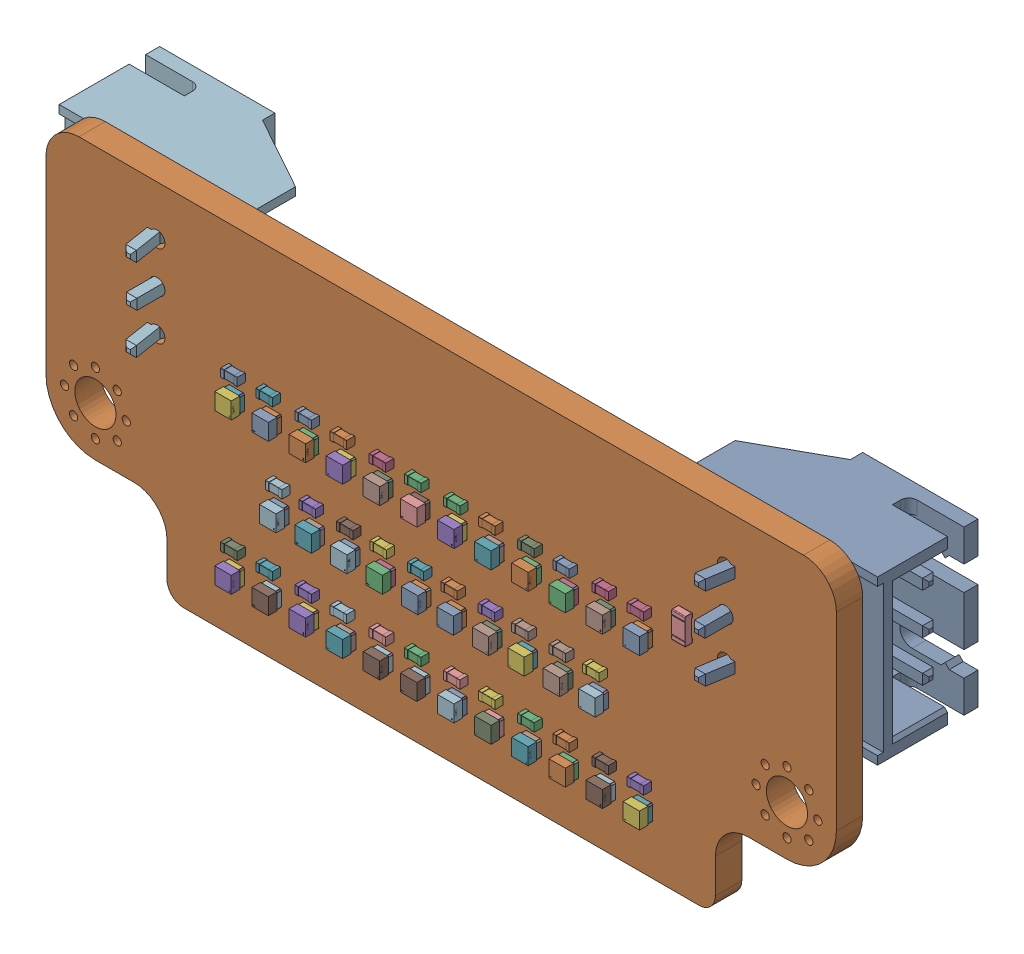
SolidWorks assembly head_logic_display(2), configuration Default. Lengths in mm.
Overall size (49.7 21.59 9.5).
143 component instances, 5 part files, 0 mates.
Components (placement in the parent):
- LED-SMD_4P-L1.0-W1.0-TL_XL-1010RGBC-WS2812B-1: LED-SMD_4P-L1.0-W1.0-TL_XL-1010RGBC-WS2812B [Default] at (-7.892 -7.295 1.65) x (0 1 0) z (0 0 1) size (1 1 0.81)
  - LED-SMD_4P-L1.0-W1.0-TL_XL-1010RGBC-WS2812B-0-1: LED-SMD_4P-L1.0-W1.0-TL_XL-1010RGBC-WS2812B-0 [Default] at origin size (1 1 0.81)
- C_0402_1005Metric-1: C_0402_1005Metric [Default] at (-10.206 3.245 1.65) x (-1 0 0) z (0 0 1) size (1 0.5 0.5)
  - C_0402_1005Metric-1-1: C_0402_1005Metric-1 [Default] at origin size (1 0.5 0.5)
- LED-SMD_4P-L1.0-W1.0-TL_XL-1010RGBC-WS2812B-2: LED-SMD_4P-L1.0-W1.0-TL_XL-1010RGBC-WS2812B [Default] at (9.7 -2.705 1.65) size (1 1 0.81)
  - LED-SMD_4P-L1.0-W1.0-TL_XL-1010RGBC-WS2812B-0-1: LED-SMD_4P-L1.0-W1.0-TL_XL-1010RGBC-WS2812B-0 [Default] at origin size (1 1 0.81)
- C_0402_1005Metric-2: C_0402_1005Metric [Default] at (7.826 -5.905 1.65) x (-1 0 0) z (0 0 1) size (1 0.5 0.5)
  - C_0402_1005Metric-1-1: C_0402_1005Metric-1 [Default] at origin size (1 0.5 0.5)
- LED-SMD_4P-L1.0-W1.0-TL_XL-1010RGBC-WS2812B-3: LED-SMD_4P-L1.0-W1.0-TL_XL-1010RGBC-WS2812B [Default] at (-5.638 -7.295 1.65) size (1 1 0.81)
  - LED-SMD_4P-L1.0-W1.0-TL_XL-1010RGBC-WS2812B-0-1: LED-SMD_4P-L1.0-W1.0-TL_XL-1010RGBC-WS2812B-0 [Default] at origin size (1 1 0.81)
- LED-SMD_4P-L1.0-W1.0-TL_XL-1010RGBC-WS2812B-4: LED-SMD_4P-L1.0-W1.0-TL_XL-1010RGBC-WS2812B [Default] at (1.084 -2.705 1.65) size (1 1 0.81)
  - LED-SMD_4P-L1.0-W1.0-TL_XL-1010RGBC-WS2812B-0-1: LED-SMD_4P-L1.0-W1.0-TL_XL-1010RGBC-WS2812B-0 [Default] at origin size (1 1 0.81)
- LED-SMD_4P-L1.0-W1.0-TL_XL-1010RGBC-WS2812B-5: LED-SMD_4P-L1.0-W1.0-TL_XL-1010RGBC-WS2812B [Default] at (3.378 1.875 1.65) size (1 1 0.81)
  - LED-SMD_4P-L1.0-W1.0-TL_XL-1010RGBC-WS2812B-0-1: LED-SMD_4P-L1.0-W1.0-TL_XL-1010RGBC-WS2812B-0 [Default] at origin size (1 1 0.81)
- LED-SMD_4P-L1.0-W1.0-TL_XL-1010RGBC-WS2812B-6: LED-SMD_4P-L1.0-W1.0-TL_XL-1010RGBC-WS2812B [Default] at (-1.07 -2.705 1.65) x (0 1 0) z (0 0 1) size (1 1 0.81)
  - LED-SMD_4P-L1.0-W1.0-TL_XL-1010RGBC-WS2812B-0-1: LED-SMD_4P-L1.0-W1.0-TL_XL-1010RGBC-WS2812B-0 [Default] at origin size (1 1 0.81)
- LED-SMD_4P-L1.0-W1.0-TL_XL-1010RGBC-WS2812B-7: LED-SMD_4P-L1.0-W1.0-TL_XL-1010RGBC-WS2812B [Default] at (-7.532 -2.705 1.65) size (1 1 0.81)
  - LED-SMD_4P-L1.0-W1.0-TL_XL-1010RGBC-WS2812B-0-1: LED-SMD_4P-L1.0-W1.0-TL_XL-1010RGBC-WS2812B-0 [Default] at origin size (1 1 0.81)
- LED-SMD_4P-L1.0-W1.0-TL_XL-1010RGBC-WS2812B-8: LED-SMD_4P-L1.0-W1.0-TL_XL-1010RGBC-WS2812B [Default] at (12.394 1.875 1.65) size (1 1 0.81)
  - LED-SMD_4P-L1.0-W1.0-TL_XL-1010RGBC-WS2812B-0-1: LED-SMD_4P-L1.0-W1.0-TL_XL-1010RGBC-WS2812B-0 [Default] at origin size (1 1 0.81)
- LED-SMD_4P-L1.0-W1.0-TL_XL-1010RGBC-WS2812B-9: LED-SMD_4P-L1.0-W1.0-TL_XL-1010RGBC-WS2812B [Default] at (5.632 -7.295 1.65) x (0 1 0) z (0 0 1) size (1 1 0.81)
  - LED-SMD_4P-L1.0-W1.0-TL_XL-1010RGBC-WS2812B-0-1: LED-SMD_4P-L1.0-W1.0-TL_XL-1010RGBC-WS2812B-0 [Default] at origin size (1 1 0.81)
- C_0402_1005Metric-3: C_0402_1005Metric [Default] at (-12.34 -5.905 1.65) size (1 0.5 0.5)
  - C_0402_1005Metric-1-1: C_0402_1005Metric-1 [Default] at origin size (1 0.5 0.5)
- LED-SMD_4P-L1.0-W1.0-TL_XL-1010RGBC-WS2812B-10: LED-SMD_4P-L1.0-W1.0-TL_XL-1010RGBC-WS2812B [Default] at (-7.892 1.875 1.65) x (0 1 0) z (0 0 1) size (1 1 0.81)
  - LED-SMD_4P-L1.0-W1.0-TL_XL-1010RGBC-WS2812B-0-1: LED-SMD_4P-L1.0-W1.0-TL_XL-1010RGBC-WS2812B-0 [Default] at origin size (1 1 0.81)
- LED-SMD_4P-L1.0-W1.0-TL_XL-1010RGBC-WS2812B-11: LED-SMD_4P-L1.0-W1.0-TL_XL-1010RGBC-WS2812B [Default] at (3.238 -2.705 1.65) x (0 1 0) z (0 0 1) size (1 1 0.81)
  - LED-SMD_4P-L1.0-W1.0-TL_XL-1010RGBC-WS2812B-0-1: LED-SMD_4P-L1.0-W1.0-TL_XL-1010RGBC-WS2812B-0 [Default] at origin size (1 1 0.81)
- R_0603_1608Metric-1: R_0603_1608Metric [Default] at (14.9 3.645 1.65) x (0 -1 0) z (0 0 1) size (1.6 0.8 0.45)
  - R_0603_1608Metric-2-1: R_0603_1608Metric-2 [Default] at origin size (1.6 0.8 0.45)
- C_0402_1005Metric-4: C_0402_1005Metric [Default] at (-5.318 -1.305 1.65) size (1 0.5 0.5)
  - C_0402_1005Metric-1-1: C_0402_1005Metric-1 [Default] at origin size (1 0.5 0.5)
- C_0402_1005Metric-5: C_0402_1005Metric [Default] at (-9.626 -1.305 1.65) size (1 0.5 0.5)
  - C_0402_1005Metric-1-1: C_0402_1005Metric-1 [Default] at origin size (1 0.5 0.5)
- LED-SMD_4P-L1.0-W1.0-TL_XL-1010RGBC-WS2812B-12: LED-SMD_4P-L1.0-W1.0-TL_XL-1010RGBC-WS2812B [Default] at (-5.638 1.875 1.65) size (1 1 0.81)
  - LED-SMD_4P-L1.0-W1.0-TL_XL-1010RGBC-WS2812B-0-1: LED-SMD_4P-L1.0-W1.0-TL_XL-1010RGBC-WS2812B-0 [Default] at origin size (1 1 0.81)
- LED-SMD_4P-L1.0-W1.0-TL_XL-1010RGBC-WS2812B-13: LED-SMD_4P-L1.0-W1.0-TL_XL-1010RGBC-WS2812B [Default] at (-1.13 -7.295 1.65) size (1 1 0.81)
  - LED-SMD_4P-L1.0-W1.0-TL_XL-1010RGBC-WS2812B-0-1: LED-SMD_4P-L1.0-W1.0-TL_XL-1010RGBC-WS2812B-0 [Default] at origin size (1 1 0.81)
- C_0402_1005Metric-6: C_0402_1005Metric [Default] at (7.826 3.245 1.65) x (-1 0 0) z (0 0 1) size (1 0.5 0.5)
  - C_0402_1005Metric-1-1: C_0402_1005Metric-1 [Default] at origin size (1 0.5 0.5)
- LED-SMD_4P-L1.0-W1.0-TL_XL-1010RGBC-WS2812B-14: LED-SMD_4P-L1.0-W1.0-TL_XL-1010RGBC-WS2812B [Default] at (-12.4 1.875 1.65) x (0 1 0) z (0 0 1) size (1 1 0.81)
  - LED-SMD_4P-L1.0-W1.0-TL_XL-1010RGBC-WS2812B-0-1: LED-SMD_4P-L1.0-W1.0-TL_XL-1010RGBC-WS2812B-0 [Default] at origin size (1 1 0.81)
- C_0402_1005Metric-7: C_0402_1005Metric [Default] at (5.332 -1.305 1.65) x (-1 0 0) z (0 0 1) size (1 0.5 0.5)
  - C_0402_1005Metric-1-1: C_0402_1005Metric-1 [Default] at origin size (1 0.5 0.5)
- C_0402_1005Metric-8: C_0402_1005Metric [Default] at (5.692 3.245 1.65) size (1 0.5 0.5)
  - C_0402_1005Metric-1-1: C_0402_1005Metric-1 [Default] at origin size (1 0.5 0.5)
- LED-SMD_4P-L1.0-W1.0-TL_XL-1010RGBC-WS2812B-15: LED-SMD_4P-L1.0-W1.0-TL_XL-1010RGBC-WS2812B [Default] at (5.632 1.875 1.65) x (0 1 0) z (0 0 1) size (1 1 0.81)
  - LED-SMD_4P-L1.0-W1.0-TL_XL-1010RGBC-WS2812B-0-1: LED-SMD_4P-L1.0-W1.0-TL_XL-1010RGBC-WS2812B-0 [Default] at origin size (1 1 0.81)
- LED-SMD_4P-L1.0-W1.0-TL_XL-1010RGBC-WS2812B-16: LED-SMD_4P-L1.0-W1.0-TL_XL-1010RGBC-WS2812B [Default] at (7.546 -2.705 1.65) x (0 1 0) z (0 0 1) size (1 1 0.81)
  - LED-SMD_4P-L1.0-W1.0-TL_XL-1010RGBC-WS2812B-0-1: LED-SMD_4P-L1.0-W1.0-TL_XL-1010RGBC-WS2812B-0 [Default] at origin size (1 1 0.81)
- C_0402_1005Metric-9: C_0402_1005Metric [Default] at (1.184 -5.905 1.65) size (1 0.5 0.5)
  - C_0402_1005Metric-1-1: C_0402_1005Metric-1 [Default] at origin size (1 0.5 0.5)
- LED-SMD_4P-L1.0-W1.0-TL_XL-1010RGBC-WS2812B-17: LED-SMD_4P-L1.0-W1.0-TL_XL-1010RGBC-WS2812B [Default] at (-3.224 -2.705 1.65) size (1 1 0.81)
  - LED-SMD_4P-L1.0-W1.0-TL_XL-1010RGBC-WS2812B-0-1: LED-SMD_4P-L1.0-W1.0-TL_XL-1010RGBC-WS2812B-0 [Default] at origin size (1 1 0.81)
- C_0402_1005Metric-10: C_0402_1005Metric [Default] at (-7.832 -5.905 1.65) size (1 0.5 0.5)
  - C_0402_1005Metric-1-1: C_0402_1005Metric-1 [Default] at origin size (1 0.5 0.5)
- C_0402_1005Metric-11: C_0402_1005Metric [Default] at (3.318 -5.905 1.65) x (-1 0 0) z (0 0 1) size (1 0.5 0.5)
  - C_0402_1005Metric-1-1: C_0402_1005Metric-1 [Default] at origin size (1 0.5 0.5)
- C_0402_1005Metric-12: C_0402_1005Metric [Default] at (-10.206 -5.905 1.65) x (-1 0 0) z (0 0 1) size (1 0.5 0.5)
  - C_0402_1005Metric-1-1: C_0402_1005Metric-1 [Default] at origin size (1 0.5 0.5)
- LED-SMD_4P-L1.0-W1.0-TL_XL-1010RGBC-WS2812B-18: LED-SMD_4P-L1.0-W1.0-TL_XL-1010RGBC-WS2812B [Default] at (-5.378 -2.705 1.65) x (0 1 0) z (0 0 1) size (1 1 0.81)
  - LED-SMD_4P-L1.0-W1.0-TL_XL-1010RGBC-WS2812B-0-1: LED-SMD_4P-L1.0-W1.0-TL_XL-1010RGBC-WS2812B-0 [Default] at origin size (1 1 0.81)
- LED-SMD_4P-L1.0-W1.0-TL_XL-1010RGBC-WS2812B-19: LED-SMD_4P-L1.0-W1.0-TL_XL-1010RGBC-WS2812B [Default] at (5.392 -2.705 1.65) size (1 1 0.81)
  - LED-SMD_4P-L1.0-W1.0-TL_XL-1010RGBC-WS2812B-0-1: LED-SMD_4P-L1.0-W1.0-TL_XL-1010RGBC-WS2812B-0 [Default] at origin size (1 1 0.81)
- LED-SMD_4P-L1.0-W1.0-TL_XL-1010RGBC-WS2812B-20: LED-SMD_4P-L1.0-W1.0-TL_XL-1010RGBC-WS2812B [Default] at (1.124 -7.295 1.65) x (0 1 0) z (0 0 1) size (1 1 0.81)
  - LED-SMD_4P-L1.0-W1.0-TL_XL-1010RGBC-WS2812B-0-1: LED-SMD_4P-L1.0-W1.0-TL_XL-1010RGBC-WS2812B-0 [Default] at origin size (1 1 0.81)
- C_0402_1005Metric-13: C_0402_1005Metric [Default] at (-5.698 3.245 1.65) x (-1 0 0) z (0 0 1) size (1 0.5 0.5)
  - C_0402_1005Metric-1-1: C_0402_1005Metric-1 [Default] at origin size (1 0.5 0.5)
- C_0402_1005Metric-14: C_0402_1005Metric [Default] at (5.692 -5.905 1.65) size (1 0.5 0.5)
  - C_0402_1005Metric-1-1: C_0402_1005Metric-1 [Default] at origin size (1 0.5 0.5)
- C_0402_1005Metric-15: C_0402_1005Metric [Default] at (12.334 3.245 1.65) x (-1 0 0) z (0 0 1) size (1 0.5 0.5)
  - C_0402_1005Metric-1-1: C_0402_1005Metric-1 [Default] at origin size (1 0.5 0.5)
- C_0402_1005Metric-16: C_0402_1005Metric [Default] at (3.298 -1.305 1.65) size (1 0.5 0.5)
  - C_0402_1005Metric-1-1: C_0402_1005Metric-1 [Default] at origin size (1 0.5 0.5)
- C_0402_1005Metric-17: C_0402_1005Metric [Default] at (-3.284 -1.305 1.65) x (-1 0 0) z (0 0 1) size (1 0.5 0.5)
  - C_0402_1005Metric-1-1: C_0402_1005Metric-1 [Default] at origin size (1 0.5 0.5)
- LED-SMD_4P-L1.0-W1.0-TL_XL-1010RGBC-WS2812B-21: LED-SMD_4P-L1.0-W1.0-TL_XL-1010RGBC-WS2812B [Default] at (-3.384 -7.295 1.65) x (0 1 0) z (0 0 1) size (1 1 0.81)
  - LED-SMD_4P-L1.0-W1.0-TL_XL-1010RGBC-WS2812B-0-1: LED-SMD_4P-L1.0-W1.0-TL_XL-1010RGBC-WS2812B-0 [Default] at origin size (1 1 0.81)
- LED-SMD_4P-L1.0-W1.0-TL_XL-1010RGBC-WS2812B-22: LED-SMD_4P-L1.0-W1.0-TL_XL-1010RGBC-WS2812B [Default] at (1.124 1.875 1.65) x (0 1 0) z (0 0 1) size (1 1 0.81)
  - LED-SMD_4P-L1.0-W1.0-TL_XL-1010RGBC-WS2812B-0-1: LED-SMD_4P-L1.0-W1.0-TL_XL-1010RGBC-WS2812B-0 [Default] at origin size (1 1 0.81)
- LED-SMD_4P-L1.0-W1.0-TL_XL-1010RGBC-WS2812B-23: LED-SMD_4P-L1.0-W1.0-TL_XL-1010RGBC-WS2812B [Default] at (10.14 -7.295 1.65) x (0 1 0) z (0 0 1) size (1 1 0.81)
  - LED-SMD_4P-L1.0-W1.0-TL_XL-1010RGBC-WS2812B-0-1: LED-SMD_4P-L1.0-W1.0-TL_XL-1010RGBC-WS2812B-0 [Default] at origin size (1 1 0.81)
- LED-SMD_4P-L1.0-W1.0-TL_XL-1010RGBC-WS2812B-24: LED-SMD_4P-L1.0-W1.0-TL_XL-1010RGBC-WS2812B [Default] at (-12.4 -7.295 1.65) x (0 1 0) z (0 0 1) size (1 1 0.81)
  - LED-SMD_4P-L1.0-W1.0-TL_XL-1010RGBC-WS2812B-0-1: LED-SMD_4P-L1.0-W1.0-TL_XL-1010RGBC-WS2812B-0 [Default] at origin size (1 1 0.81)
- LED-SMD_4P-L1.0-W1.0-TL_XL-1010RGBC-WS2812B-25: LED-SMD_4P-L1.0-W1.0-TL_XL-1010RGBC-WS2812B [Default] at (-10.146 -7.295 1.65) size (1 1 0.81)
  - LED-SMD_4P-L1.0-W1.0-TL_XL-1010RGBC-WS2812B-0-1: LED-SMD_4P-L1.0-W1.0-TL_XL-1010RGBC-WS2812B-0 [Default] at origin size (1 1 0.81)
- C_0402_1005Metric-18: C_0402_1005Metric [Default] at (-12.34 3.245 1.65) size (1 0.5 0.5)
  - C_0402_1005Metric-1-1: C_0402_1005Metric-1 [Default] at origin size (1 0.5 0.5)
- C_0402_1005Metric-19: C_0402_1005Metric [Default] at (3.318 3.245 1.65) x (-1 0 0) z (0 0 1) size (1 0.5 0.5)
  - C_0402_1005Metric-1-1: C_0402_1005Metric-1 [Default] at origin size (1 0.5 0.5)
- C_0402_1005Metric-20: C_0402_1005Metric [Default] at (-1.19 3.245 1.65) x (-1 0 0) z (0 0 1) size (1 0.5 0.5)
  - C_0402_1005Metric-1-1: C_0402_1005Metric-1 [Default] at origin size (1 0.5 0.5)
- C_0402_1005Metric-21: C_0402_1005Metric [Default] at (-3.324 3.245 1.65) size (1 0.5 0.5)
  - C_0402_1005Metric-1-1: C_0402_1005Metric-1 [Default] at origin size (1 0.5 0.5)
- C_0402_1005Metric-22: C_0402_1005Metric [Default] at (-7.592 -1.305 1.65) x (-1 0 0) z (0 0 1) size (1 0.5 0.5)
  - C_0402_1005Metric-1-1: C_0402_1005Metric-1 [Default] at origin size (1 0.5 0.5)
- C_0402_1005Metric-23: C_0402_1005Metric [Default] at (9.64 -1.305 1.65) x (-1 0 0) z (0 0 1) size (1 0.5 0.5)
  - C_0402_1005Metric-1-1: C_0402_1005Metric-1 [Default] at origin size (1 0.5 0.5)
- C_0402_1005Metric-24: C_0402_1005Metric [Default] at (-1.01 -1.305 1.65) size (1 0.5 0.5)
  - C_0402_1005Metric-1-1: C_0402_1005Metric-1 [Default] at origin size (1 0.5 0.5)
- LED-SMD_4P-L1.0-W1.0-TL_XL-1010RGBC-WS2812B-26: LED-SMD_4P-L1.0-W1.0-TL_XL-1010RGBC-WS2812B [Default] at (-9.686 -2.705 1.65) x (0 1 0) z (0 0 1) size (1 1 0.81)
  - LED-SMD_4P-L1.0-W1.0-TL_XL-1010RGBC-WS2812B-0-1: LED-SMD_4P-L1.0-W1.0-TL_XL-1010RGBC-WS2812B-0 [Default] at origin size (1 1 0.81)
- LED-SMD_4P-L1.0-W1.0-TL_XL-1010RGBC-WS2812B-27: LED-SMD_4P-L1.0-W1.0-TL_XL-1010RGBC-WS2812B [Default] at (12.394 -7.295 1.65) size (1 1 0.81)
  - LED-SMD_4P-L1.0-W1.0-TL_XL-1010RGBC-WS2812B-0-1: LED-SMD_4P-L1.0-W1.0-TL_XL-1010RGBC-WS2812B-0 [Default] at origin size (1 1 0.81)
- C_0402_1005Metric-25: C_0402_1005Metric [Default] at (7.606 -1.305 1.65) size (1 0.5 0.5)
  - C_0402_1005Metric-1-1: C_0402_1005Metric-1 [Default] at origin size (1 0.5 0.5)
- LED-SMD_4P-L1.0-W1.0-TL_XL-1010RGBC-WS2812B-28: LED-SMD_4P-L1.0-W1.0-TL_XL-1010RGBC-WS2812B [Default] at (-10.146 1.875 1.65) size (1 1 0.81)
  - LED-SMD_4P-L1.0-W1.0-TL_XL-1010RGBC-WS2812B-0-1: LED-SMD_4P-L1.0-W1.0-TL_XL-1010RGBC-WS2812B-0 [Default] at origin size (1 1 0.81)
- C_0402_1005Metric-26: C_0402_1005Metric [Default] at (-1.19 -5.905 1.65) x (-1 0 0) z (0 0 1) size (1 0.5 0.5)
  - C_0402_1005Metric-1-1: C_0402_1005Metric-1 [Default] at origin size (1 0.5 0.5)
- LED-SMD_4P-L1.0-W1.0-TL_XL-1010RGBC-WS2812B-29: LED-SMD_4P-L1.0-W1.0-TL_XL-1010RGBC-WS2812B [Default] at (-3.384 1.875 1.65) x (0 1 0) z (0 0 1) size (1 1 0.81)
  - LED-SMD_4P-L1.0-W1.0-TL_XL-1010RGBC-WS2812B-0-1: LED-SMD_4P-L1.0-W1.0-TL_XL-1010RGBC-WS2812B-0 [Default] at origin size (1 1 0.81)
- LED-SMD_4P-L1.0-W1.0-TL_XL-1010RGBC-WS2812B-30: LED-SMD_4P-L1.0-W1.0-TL_XL-1010RGBC-WS2812B [Default] at (7.886 -7.295 1.65) size (1 1 0.81)
  - LED-SMD_4P-L1.0-W1.0-TL_XL-1010RGBC-WS2812B-0-1: LED-SMD_4P-L1.0-W1.0-TL_XL-1010RGBC-WS2812B-0 [Default] at origin size (1 1 0.81)
- C_0402_1005Metric-27: C_0402_1005Metric [Default] at (10.2 3.245 1.65) size (1 0.5 0.5)
  - C_0402_1005Metric-1-1: C_0402_1005Metric-1 [Default] at origin size (1 0.5 0.5)
- C_0402_1005Metric-28: C_0402_1005Metric [Default] at (12.334 -5.905 1.65) x (-1 0 0) z (0 0 1) size (1 0.5 0.5)
  - C_0402_1005Metric-1-1: C_0402_1005Metric-1 [Default] at origin size (1 0.5 0.5)
- LED-SMD_4P-L1.0-W1.0-TL_XL-1010RGBC-WS2812B-31: LED-SMD_4P-L1.0-W1.0-TL_XL-1010RGBC-WS2812B [Default] at (-1.13 1.875 1.65) size (1 1 0.81)
  - LED-SMD_4P-L1.0-W1.0-TL_XL-1010RGBC-WS2812B-0-1: LED-SMD_4P-L1.0-W1.0-TL_XL-1010RGBC-WS2812B-0 [Default] at origin size (1 1 0.81)
- C_0402_1005Metric-29: C_0402_1005Metric [Default] at (-5.698 -5.905 1.65) x (-1 0 0) z (0 0 1) size (1 0.5 0.5)
  - C_0402_1005Metric-1-1: C_0402_1005Metric-1 [Default] at origin size (1 0.5 0.5)
- C_0402_1005Metric-30: C_0402_1005Metric [Default] at (-7.832 3.245 1.65) size (1 0.5 0.5)
  - C_0402_1005Metric-1-1: C_0402_1005Metric-1 [Default] at origin size (1 0.5 0.5)
- C_0402_1005Metric-31: C_0402_1005Metric [Default] at (1.024 -1.305 1.65) x (-1 0 0) z (0 0 1) size (1 0.5 0.5)
  - C_0402_1005Metric-1-1: C_0402_1005Metric-1 [Default] at origin size (1 0.5 0.5)
- C_0402_1005Metric-32: C_0402_1005Metric [Default] at (1.184 3.245 1.65) size (1 0.5 0.5)
  - C_0402_1005Metric-1-1: C_0402_1005Metric-1 [Default] at origin size (1 0.5 0.5)
- LED-SMD_4P-L1.0-W1.0-TL_XL-1010RGBC-WS2812B-32: LED-SMD_4P-L1.0-W1.0-TL_XL-1010RGBC-WS2812B [Default] at (10.14 1.875 1.65) x (0 1 0) z (0 0 1) size (1 1 0.81)
  - LED-SMD_4P-L1.0-W1.0-TL_XL-1010RGBC-WS2812B-0-1: LED-SMD_4P-L1.0-W1.0-TL_XL-1010RGBC-WS2812B-0 [Default] at origin size (1 1 0.81)
- C_0402_1005Metric-33: C_0402_1005Metric [Default] at (-3.324 -5.905 1.65) size (1 0.5 0.5)
  - C_0402_1005Metric-1-1: C_0402_1005Metric-1 [Default] at origin size (1 0.5 0.5)
- LED-SMD_4P-L1.0-W1.0-TL_XL-1010RGBC-WS2812B-33: LED-SMD_4P-L1.0-W1.0-TL_XL-1010RGBC-WS2812B [Default] at (7.886 1.875 1.65) size (1 1 0.81)
  - LED-SMD_4P-L1.0-W1.0-TL_XL-1010RGBC-WS2812B-0-1: LED-SMD_4P-L1.0-W1.0-TL_XL-1010RGBC-WS2812B-0 [Default] at origin size (1 1 0.81)
- LED-SMD_4P-L1.0-W1.0-TL_XL-1010RGBC-WS2812B-34: LED-SMD_4P-L1.0-W1.0-TL_XL-1010RGBC-WS2812B [Default] at (3.378 -7.295 1.65) size (1 1 0.81)
  - LED-SMD_4P-L1.0-W1.0-TL_XL-1010RGBC-WS2812B-0-1: LED-SMD_4P-L1.0-W1.0-TL_XL-1010RGBC-WS2812B-0 [Default] at origin size (1 1 0.81)
- C_0402_1005Metric-34: C_0402_1005Metric [Default] at (10.2 -5.905 1.65) size (1 0.5 0.5)
  - C_0402_1005Metric-1-1: C_0402_1005Metric-1 [Default] at origin size (1 0.5 0.5)
- JST_XH_S3B-XH-A-1_1x03_P2.50mm_Horizontal-1: JST_XH_S3B-XH-A-1_1x03_P2.50mm_Horizontal [Default] at (-17.25 2.795 -0.05) x (0 1 0) z (0 0 -1) size (9.9 11.5 9.5)
  - JST_S3B_XH_A_1-1: JST_S3B_XH_A_1 [Default] at origin size (9.9 11.5 9.5)
- JST_XH_S3B-XH-A-1_1x03_P2.50mm_Horizontal-2: JST_XH_S3B-XH-A-1_1x03_P2.50mm_Horizontal [Default] at (17.25 7.795 -0.05) x (0 -1 0) z (0 0 -1) size (9.9 11.5 9.5)
  - JST_S3B_XH_A_1-1: JST_S3B_XH_A_1 [Default] at origin size (9.9 11.5 9.5)
- head_logic_display_PCB-1: head_logic_display_PCB [Default] at origin size (48 21.59 1.6)
